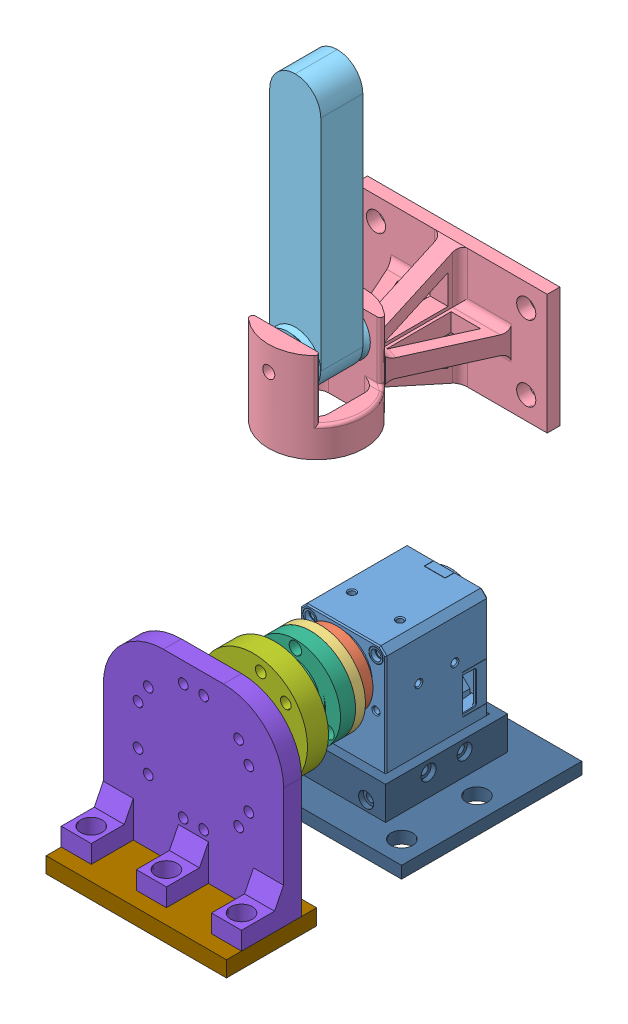
SolidWorks assembly exp_stiff, configuration 기본. Lengths in mm.
Overall size (66.5 219.33 117.6).
10 component instances, 10 part files, 19 mates.
Components (placement in the parent):
- xm-430_idle(stp)-1: xm-430_idle(stp) [기본] at (-8.3249 8.7981 44.3001) size (28.5 46.5 42.4)
- SEA_motor_v5-1: SEA_motor_v5 [기본] at (-8.3249 8.7981 63.3001) size (24 24 5.5)
- SEA_pulley_v5_part1-1: SEA_pulley_v5_part1 [기본] at (-8.3249 8.7981 68.8001) size (30 29.39 3.3)
- rod_hold-1: rod_hold [기본] at (-6.3249 95.3811 23.1001) x (0 -1 0) z (0 0 1) size (40 64 65)
- rod-1: rod [기본] at (-6.3249 143.8811 72.1724) size (17 90 19)
- SEA_pulley_part2_stifftest-2: SEA_pulley_part2_stifftest [기본] at (-8.3249 8.7981 72.1001) size (30 30 12)
- SEA_pulley_f_v4-2: SEA_pulley_f_v4 [기본] at (-8.3249 8.7981 84.1001) size (36 36 7)
- torque_holder-1: torque_holder [기본] at (-6.478 4.7981 106.9001) size (60 60 20)
- torque_holder_plate-1: torque_holder_plate [기본] at (-6.478 -25.2019 116.9001) x (0 0 -1) z (0 -1 0) size (30 60 5.25)
- motor_hold_stifftest-1: motor_hold_stifftest [기본] at (-8.3249 -30.4519 44.3001) x (0 0 1) z (0 1 0) size (60 65 15)
Mates (geometry in assembly coordinates):
- 동심1: concentric anti-aligned: circle of xm-430_idle(stp)-1; circle of SEA_motor_v5-1
- 일치1: coincident anti-aligned: plane of xm-430_idle(stp)-1 through (-8.3249 8.7981 63.3001) normal (0 0 1); plane of SEA_motor_v5-1 through (-8.3249 8.7981 63.3001) normal (0 0 -1)
- 동심2: concentric aligned: cylinder of xm-430_idle(stp)-1 through (-8.3249 16.7981 60.6954) axis (0 0 1) radius 0.8; cylinder of SEA_motor_v5-1 through (-8.3249 16.7981 57.3604) axis (0 0 1) radius 2.1
- 동심3: concentric aligned: cylinder of SEA_motor_v5-1 through (-8.3249 8.7981 68.8001) axis (0 0 -1) radius 12; cylinder of SEA_pulley_v5_part1-1 through (-8.3249 8.7981 72.1001) axis (0 0 -1) radius 15
- 동심4: concentric aligned: cylinder of SEA_motor_v5-1 through (-1.6074 15.5156 68.8001) axis (0 0 -1) radius 1; cylinder of SEA_pulley_v5_part1-1 through (-1.6074 15.5156 72.1001) axis (0 0 -1) radius 1.1
- 일치2: coincident anti-aligned: plane of SEA_motor_v5-1 through (-8.3249 8.7981 68.8001) normal (0 0 1); plane of SEA_pulley_v5_part1-1 through (-8.3249 8.7981 68.8001) normal (0 0 -1)
- 동심10: concentric aligned: cylinder of rod_hold-1 through (-6.3249 107.3811 88.1011) axis (0 0 -1) radius 2; cylinder of rod-1 through (-6.3249 107.3811 79.1724) axis (0 0 -1) radius 3.6
- 동심13: concentric aligned: cylinder of SEA_pulley_v5_part1-1 through (-8.3249 21.2981 72.1001) axis (0 0 -1) radius 1; cylinder of SEA_pulley_part2_stifftest-2 through (-8.3249 21.2981 73.5001) axis (0 0 -1) radius 1.2
- 일치11: coincident anti-aligned: plane of SEA_pulley_v5_part1-1 through (-8.3249 8.7981 72.1001) normal (0 0 1); plane of SEA_pulley_part2_stifftest-2 through (-8.3249 8.7981 72.1001) normal (0 0 -1)
- 동심14: concentric anti-aligned: cylinder of SEA_pulley_part2_stifftest-2 through (-8.3249 12.7981 84.1001) axis (0 0 -1) radius 0.95; cylinder of SEA_pulley_f_v4-2 through (-8.3249 12.7981 85.5001) axis (0 0 1) radius 2.1
- 일치12: coincident anti-aligned: plane of SEA_pulley_part2_stifftest-2 through (-8.3249 8.7981 84.1001) normal (0 0 1); plane of SEA_pulley_f_v4-2 through (-8.3249 8.7981 84.1001) normal (0 0 -1)
- 거리1: distance = 15.8 mm anti-aligned: plane of torque_holder-1 through (-6.478 4.7981 106.9001) normal (0 0 -1); plane of SEA_pulley_f_v4-2 through (-8.3249 8.7981 91.1001) normal (0 0 1)
- 일치16: coincident anti-aligned: plane of torque_holder-1 through (-36.478 -28.5661 112.9001) normal (0 -1 0); plane of torque_holder_plate-1 through (-6.478 -28.5661 116.9001) normal (0 1 0)
- 일치17: coincident aligned: plane of torque_holder-1 through (23.522 31.4339 112.9001) normal (1 0 0); plane of torque_holder_plate-1 through (23.522 -33.8161 101.9001) normal (1 0 0)
- 동심15: concentric aligned: cylinder of torque_holder-1 through (18.522 -37.5661 121.9001) axis (0 1 0) radius 3.625; cylinder of torque_holder_plate-1 through (18.522 -33.8161 121.9001) axis (0 1 0) radius 3.625
- 일치19: coincident anti-aligned: plane of xm-430_idle(stp)-1 through (-22.5749 -26.4519 27.3001) normal (0 -1 0); plane of motor_hold_stifftest-1 through (-8.3249 -26.4519 44.3001) normal (0 1 0)
- 동심16: concentric anti-aligned: cylinder of xm-430_idle(stp)-1 through (2.1284 -19.2019 38.3001) axis (1 0 0) radius 1.025; cylinder of motor_hold_stifftest-1 through (24.1751 -19.2019 38.3001) axis (-1 0 0) radius 1.5
- 동심17: concentric aligned: cylinder of xm-430_idle(stp)-1 through (2.6751 -23.2019 27.3001) axis (0 0 -1) radius 1.3; cylinder of motor_hold_stifftest-1 through (2.6751 -23.2019 25.6001) axis (0 0 -1) radius 2.5
- 일치22: coincident aligned: plane of torque_holder_plate-1 through (-6.478 -30.4519 116.9001) normal (0 -1 0); plane of motor_hold_stifftest-1 through (-8.3249 -30.4519 44.3001) normal (0 -1 0)
